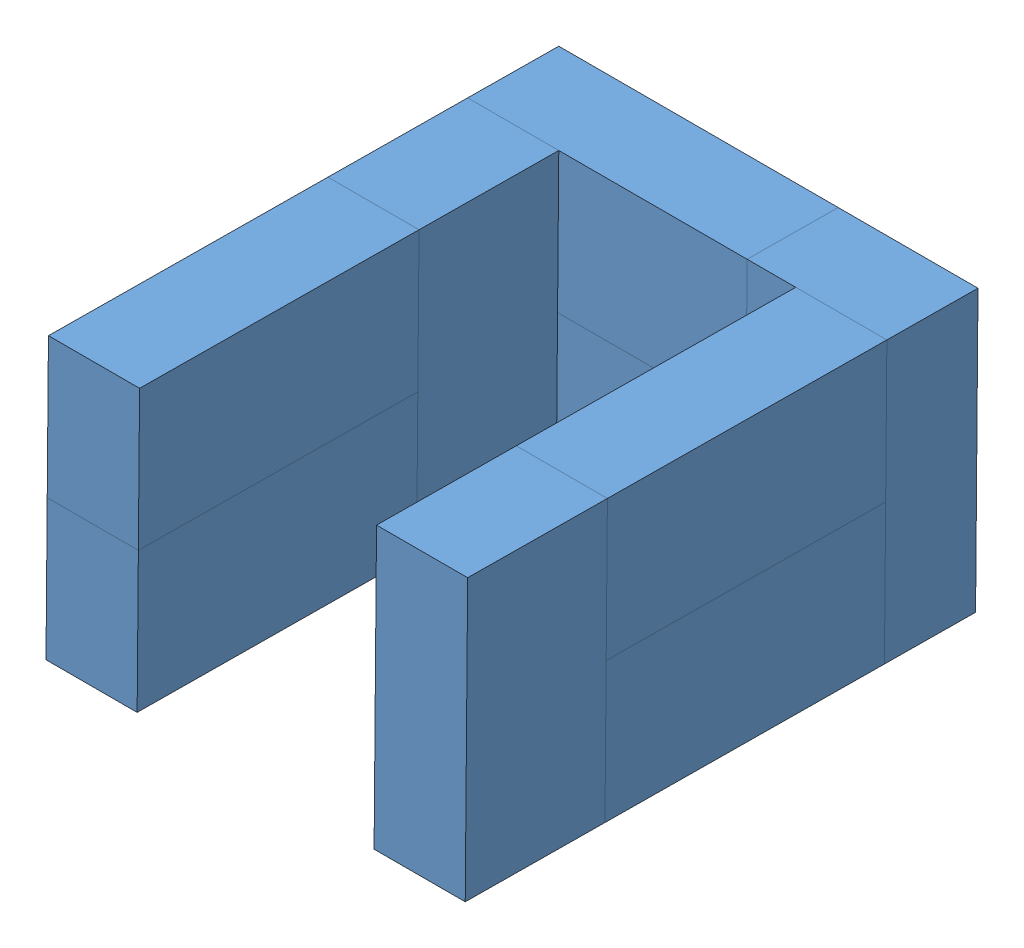
SolidWorks assembly Assem1, configuration Default. Lengths in mm.
Overall size (345 233.66 421.99).
9 component instances, 1 part files, 14 mates.
Components (placement in the parent):
- Brick-Sharp-1: Brick-Sharp [Default] at (31.4801 230.0802 130.4676) x (1 0 0) z (0 -0.999962 0.008727) size (230 75 115)
- Brick-Sharp-3: Brick-Sharp [Default] at (31.4801 345.0758 129.4641) x (1 0 0) z (0 -0.999962 0.008727) size (230 75 115)
- Brick-Sharp-5: Brick-Sharp [Default] at (-46.0199 288.4071 224.9622) x (0 -0.999962 0.008727) z (0 0.008727 0.999962) size (230 75 115)
- Brick-Sharp-6: Brick-Sharp [Default] at (203.9801 287.578 129.9659) x (0 0.999962 -0.008727) z (1 0 0) size (230 75 115)
- Brick-Sharp-7: Brick-Sharp [Default] at (223.9801 290.4142 454.9535) x (0 -0.999962 0.008727) z (0 0.008727 0.999962) size (230 75 115)
- Brick-Sharp-8: Brick-Sharp [Default] at (223.9801 346.4066 281.9583) x (0 0.008727 0.999962) z (0 -0.999962 0.008727) size (230 75 115)
- Brick-Sharp-9: Brick-Sharp [Default] at (-46.0199 232.4146 397.9574) x (0 0.008727 0.999962) z (0 0.999962 -0.008727) size (230 75 115)
- Brick-Sharp-10: Brick-Sharp [Default] at (-46.0199 347.4102 396.9539) x (0 0.008727 0.999962) z (0 -0.999962 0.008727) size (230 75 115)
- Brick-Sharp-11: Brick-Sharp [Default] at (223.9801 231.411 282.9618) x (0 -0.008727 -0.999962) z (0 0.999962 -0.008727) size (230 75 115)
Mates (geometry in assembly coordinates):
- Coincident1: coincident anti-aligned: line of Brick-Sharp-1 through (-83.5199 172.9097 168.468) axis (1 0 0); line of Brick-Sharp-5 through (-8.5199 172.9097 168.468) axis (-1 0 0)
- Coincident2: coincident anti-aligned: line of Brick-Sharp-1 through (-83.5199 287.9053 167.4644) axis (0 -0.999962 0.008727); line of Brick-Sharp-5 through (-83.5199 172.9097 168.468) axis (0 0.999962 -0.008727)
- Coincident4: coincident anti-aligned: line of Brick-Sharp-3 through (146.4801 287.9053 167.4644) axis (0 0.999962 -0.008727); line of Brick-Sharp-6 through (146.4801 402.9009 166.4609) axis (0 -0.999962 0.008727)
- Coincident5: coincident aligned: line of Brick-Sharp-1 through (146.4801 172.9097 168.468) axis (0 -0.008727 -0.999962); line of Brick-Sharp-6 through (146.4801 172.9097 168.468) axis (0 -0.008727 -0.999962)
- Coincident20: coincident anti-aligned: line of Brick-Sharp-5 through (-83.5199 403.9045 281.4565) axis (0 -0.999962 0.008727); line of Brick-Sharp-9 through (-83.5199 173.9132 283.4636) axis (0 0.999962 -0.008727)
- Coincident21: coincident aligned: line of Brick-Sharp-5 through (-8.5199 173.9132 283.4636) axis (-1 0 0); line of Brick-Sharp-9 through (-8.5199 173.9132 283.4636) axis (-1 0 0)
- Coincident22: coincident aligned: line of Brick-Sharp-9 through (-83.5199 288.9088 282.46) axis (0 0.008727 0.999962); line of Brick-Sharp-10 through (-83.5199 288.9088 282.46) axis (0 0.008727 0.999962)
- Coincident23: coincident aligned: line of Brick-Sharp-5 through (-83.5199 403.9045 281.4565) axis (0 -0.999962 0.008727); line of Brick-Sharp-10 through (-83.5199 403.9045 281.4565) axis (0 -0.999962 0.008727)
- Coincident24: coincident aligned: line of Brick-Sharp-6 through (146.4801 172.9097 168.468) axis (1 0 0); line of Brick-Sharp-11 through (186.4801 172.9097 168.468) axis (1 0 0)
- Coincident25: coincident anti-aligned: line of Brick-Sharp-6 through (261.4801 172.9097 168.468) axis (0 0.999962 -0.008727); line of Brick-Sharp-11 through (261.4801 287.9053 167.4644) axis (0 -0.999962 0.008727)
- Coincident26: coincident: line of Brick-Sharp-8 through (261.4801 287.9053 167.4644) axis (0 0.008727 0.999962); line of Brick-Sharp-11 through (261.4801 289.9124 397.4557) axis (0 -0.008727 -0.999962)
- Coincident27: coincident anti-aligned: line of Brick-Sharp-6 through (261.4801 172.9097 168.468) axis (0 0.999962 -0.008727); line of Brick-Sharp-8 through (261.4801 402.9009 166.4609) axis (0 -0.999962 0.008727)
- Coincident28: coincident: line of Brick-Sharp-7 through (261.4801 174.9168 398.4592) axis (0 0.999962 -0.008727); line of Brick-Sharp-8 through (261.4801 289.9124 397.4557) axis (0 0.999962 -0.008727)
- Coincident29: coincident anti-aligned: line of Brick-Sharp-7 through (261.4801 174.9168 398.4592) axis (-1 0 0); line of Brick-Sharp-11 through (186.4801 174.9168 398.4592) axis (1 0 0)
